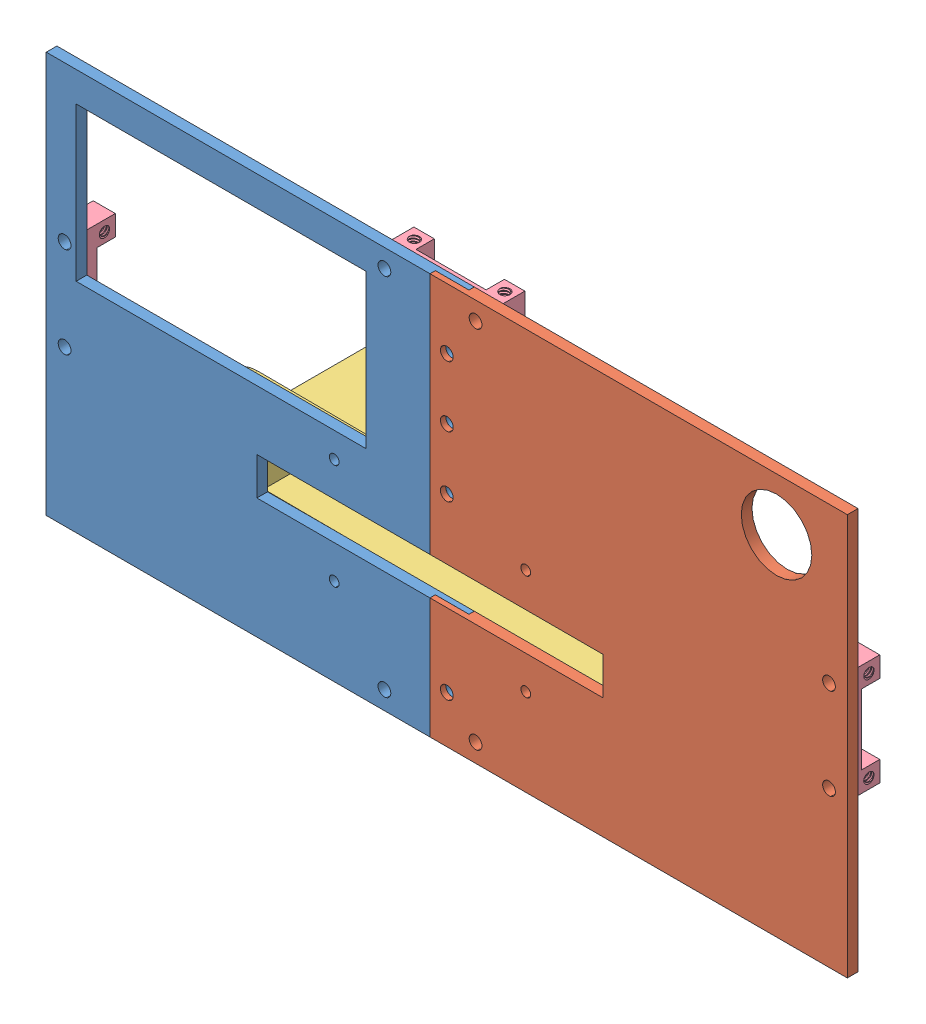
SolidWorks assembly Assem1, configuration Default. Lengths in mm.
Overall size (238.34 119.38 38.18).
7 component instances, 4 part files, 22 mates.
Components (placement in the parent):
- Half_Left_Back-1: Half_Left_Back [Default] at (-10.8392 120.2847 99.2571) size (124.17 119.38 3.18)
- Half_Right_Back-1: Half_Right_Back [Default] at (143.3908 96.3017 99.2521) size (124.17 119.38 3.18)
- USB_hub_mount-1: USB_hub_mount [Default] at (91.7146 52.0823 99.2521) x (-0.999984 0.005693 0) z (0 0 -1) size (135 41.5 35)
- Dual Side Mount_Plate.step-1: Dual Side Mount_Plate.step [Default] at (204.0238 52.9815 99.2521) x (0 1 0) z (0 0 1) size (33.02 6.58 8.63)
- Dual Side Mount_Plate.step-3: Dual Side Mount_Plate.step [Default] at (65.4239 120.3631 99.2571) size (33.02 6.58 8.63)
- Dual Side Mount_Plate.step-5: Dual Side Mount_Plate.step [Default] at (-23.4172 52.984 99.2571) x (0 1 0) z (0 0 1) size (33.02 6.58 8.63)
- Dual Side Mount_Plate.step-7: Dual Side Mount_Plate.step [Default] at (65.4219 11.8871 99.2571) size (33.02 6.58 8.63)
Mates (geometry in assembly coordinates):
- Coincident4: coincident anti-aligned: line of Half_Left_Back-1 through (87.0145 111.0219 99.2571) axis (0 0 1); line of Half_Right_Back-1 through (87.0145 111.0219 102.4321) axis (0 0 -1)
- Parallel2: parallel anti-aligned: line of Half_Left_Back-1 through (87.0145 92.9394 99.2571) axis (0 0 1); line of Half_Right_Back-1 through (87.0145 92.9319 102.4321) axis (0 0 -1)
- Parallel3: parallel anti-aligned: line of Half_Left_Back-1 through (87.0145 74.8539 99.2571) axis (0 0 1); line of Half_Right_Back-1 through (87.0145 74.8489 102.4321) axis (0 0 -1)
- Parallel4: parallel anti-aligned: line of Half_Left_Back-1 through (87.0145 23.7244 99.2571) axis (0 0 1); line of Half_Right_Back-1 through (87.0145 23.7219 102.4321) axis (0 0 -1)
- Parallel5: parallel aligned: plane of Half_Left_Back-1 through (-32.1585 129.1044 102.4321) normal (0 1 0); plane of Half_Right_Back-1 through (82.0145 129.1019 102.4321) normal (0 1 0)
- Coincident9: coincident: line of Half_Left_Back-1 through (82.0145 129.1044 100.8421) axis (1 0 0); plane of Half_Right_Back-1 through (92.0145 129.1019 100.8421) normal (0 0 -1)
- Coincident10: coincident anti-aligned: line of Half_Right_Back-1 through (110.5145 66.9829 102.4321) axis (0 0 -1); line of USB_hub_mount-1 through (110.5145 66.9829 96.2521) axis (0 0 1)
- Coincident11: coincident anti-aligned: line of Half_Left_Back-1 through (53.5145 66.9854 102.4321) axis (0 0 -1); line of USB_hub_mount-1 through (53.5136 66.9854 96.2521) axis (0 0 1)
- Parallel6: parallel anti-aligned: line of Half_Left_Back-1 through (53.5145 35.6354 102.4321) axis (0 0 -1); line of USB_hub_mount-1 through (53.3351 35.6359 96.2521) axis (0 0 1)
- Parallel7: parallel anti-aligned: line of Half_Right_Back-1 through (110.5145 35.6329 102.4321) axis (0 0 -1); line of USB_hub_mount-1 through (110.336 35.6334 96.2521) axis (0 0 1)
- Coincident14: coincident anti-aligned: plane of Half_Right_Back-1 through (143.3908 96.3017 99.2521) normal (0 0 -1); plane of USB_hub_mount-1 through (91.7146 52.0823 99.2521) normal (0 0 1)
- Coincident15: coincident anti-aligned: line of Half_Right_Back-1 through (200.7345 82.9619 102.4321) axis (0 0 -1); line of Dual Side Mount_Plate.step-1 through (200.7345 82.9619 98.6324) axis (0 0 1)
- Parallel8: parallel anti-aligned: line of Half_Right_Back-1 through (200.7345 55.8619 102.4321) axis (0 0 -1); line of Dual Side Mount_Plate.step-1 through (200.7345 56.0211 98.6367) axis (0 0 1)
- Coincident17: coincident anti-aligned: plane of Half_Right_Back-1 through (143.3908 96.3017 99.2521) normal (0 0 -1); plane of Dual Side Mount_Plate.step-1 through (197.4452 52.9815 99.2521) normal (0 0 1)
- Coincident21: coincident anti-aligned: line of Half_Left_Back-1 through (68.4635 123.6524 102.4321) axis (0 0 -1); line of Dual Side Mount_Plate.step-3 through (68.4635 123.6524 98.6417) axis (0 0 1)
- Coincident33: coincident anti-aligned: line of Half_Left_Back-1 through (-26.7065 82.9644 102.4321) axis (0 0 -1); line of Dual Side Mount_Plate.step-5 through (-26.7065 82.9644 98.6374) axis (0 0 1)
- Parallel16: parallel anti-aligned: line of Half_Left_Back-1 through (-26.7065 55.8624 102.4321) axis (0 0 -1); line of Dual Side Mount_Plate.step-5 through (-26.7065 56.0236 98.6417) axis (0 0 1)
- Coincident36: coincident anti-aligned: plane of Half_Left_Back-1 through (-10.8392 120.2847 99.2571) normal (0 0 -1); plane of Dual Side Mount_Plate.step-5 through (-29.9958 52.984 99.2571) normal (0 0 1)
- Coincident38: coincident: line of assembly; line of assembly; axis of Half_Left_Back-1 through (68.4615 15.1764 102.4321) axis (0 0 -1); axis of Dual Side Mount_Plate.step-7 through (68.4615 15.1764 98.6417) axis (0 0 1)
- Parallel18: parallel: line of Half_Right_Back-1 through (95.5645 15.1739 102.4321) axis (0 0 -1); line of Dual Side Mount_Plate.step-7 through (95.4022 15.1764 98.6374) axis (0 0 1)
- Coincident40: coincident: plane of Half_Left_Back-1 through (-10.8392 120.2847 99.2571) normal (0 0 -1); plane of Dual Side Mount_Plate.step-7 through (65.4219 18.4657 99.2571) normal (0 0 1)
- Parallel19: parallel aligned: line of Half_Right_Back-1 through (95.5645 15.1739 102.4321) axis (0 0 -1); line of Dual Side Mount_Plate.step-7 through (95.4022 15.1764 99.4835) axis (0 0 -1)
